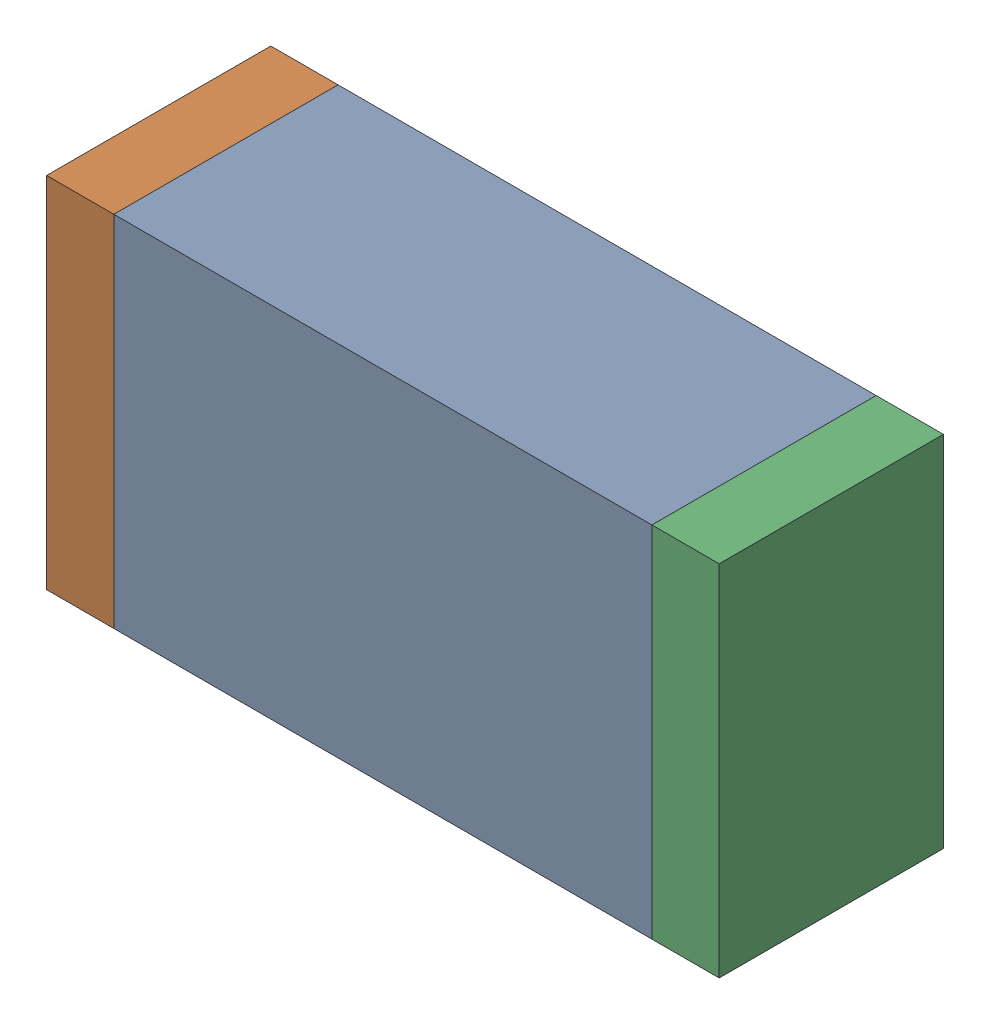
SolidWorks assembly D13, configuration Default. Lengths in mm.
Overall size (1.5 0.8 0.5).
6 component instances, 2 part files, 0 mates.
Components (placement in the parent):
- 836752368-1: 836752368 [Default] at (111.2 29.25 0) size (1.2 0.8 0.5)
  - Extruded-1: Extruded [Default] at origin size (1.2 0.8 0.5)
- 836752496-1: 836752496 [Default] at (110.525 29.25 0) size (0.15 0.8 0.5)
  - Extruded_2-1: Extruded_2 [Default] at origin size (0.15 0.8 0.5)
- 836752496-2: 836752496 [Default] at (111.875 29.25 0) size (0.15 0.8 0.5)
  - Extruded_2-1: Extruded_2 [Default] at origin size (0.15 0.8 0.5)
